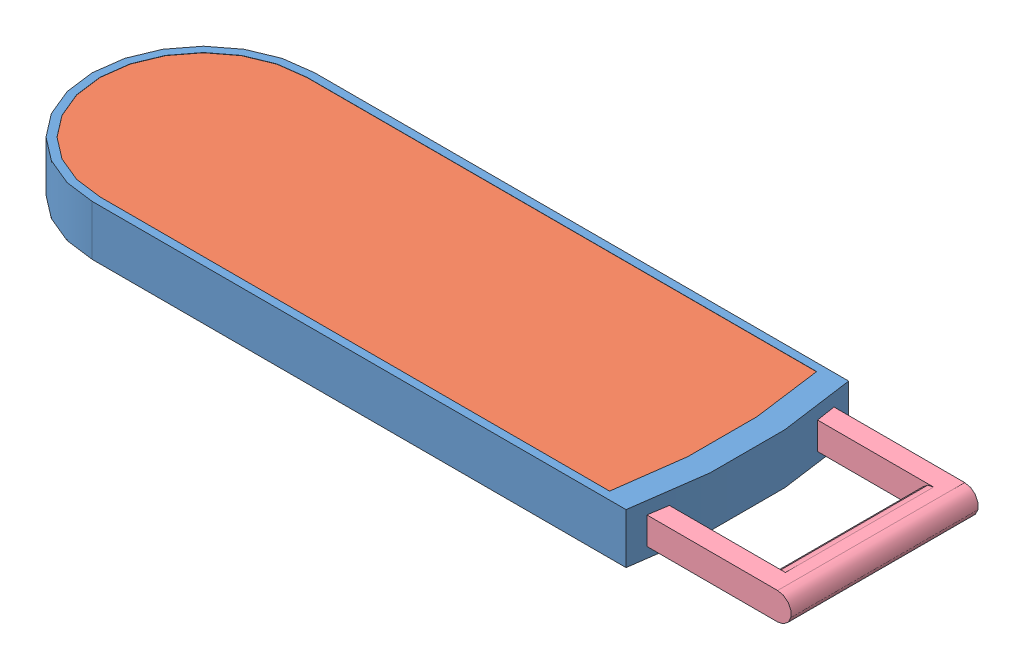
SolidWorks assembly Drawer, configuration Default. Lengths in mm.
Overall size (203.59 12.9 57.15).
4 component instances, 4 part files, 9 mates.
Components (placement in the parent):
- Drawer-1: Drawer [Default] at (12.6564 98.023 116.6708) size (168.57 12.9 57.15)
- Drawer_Cover-1: Drawer_Cover [Default] at (12.6564 106.923 116.6708) size (160.08 1.95 53.15)
- Pb-1: Pb [Default] at (12.6564 98.023 116.6708) size (133.5 8.9 53.15)
- Drawer_Handle-1: Drawer_Handle [Default] at (12.6564 98.923 116.6708) x (1 0 0.000592) z (-0.000592 0 1) size (37.07 7 48)
Mates (geometry in assembly coordinates):
- Coincident4: coincident anti-aligned: plane of Drawer-1 through (12.6564 98.023 116.6708) normal (0 1 0); plane of Pb-1 through (12.6564 98.023 116.6708) normal (0 -1 0)
- Coincident6: coincident anti-aligned: plane of Drawer-1 through (12.6564 108.923 143.2458) normal (0 0 -1); plane of Pb-1 through (12.6564 106.923 143.2458) normal (0 0 1)
- Concentric1: concentric aligned: cylinder of Drawer-1 through (12.6564 108.923 116.6708) axis (0 -1 0) radius 133.5; cylinder of Pb-1 through (12.6564 106.923 116.6708) axis (0 -1 0) radius 133.5
- Coincident7: coincident anti-aligned: plane of Drawer-1 through (12.6564 108.923 143.2458) normal (0 0 -1); plane of Drawer_Cover-1 through (12.6564 108.873 143.2458) normal (0 0 1)
- Coincident8: coincident anti-aligned: plane of Drawer_Cover-1 through (12.6564 106.923 116.6708) normal (0 -1 0); plane of Pb-1 through (12.6564 106.923 116.6708) normal (0 1 0)
- Coincident9: coincident aligned: circle of Drawer-1; cylinder of Drawer_Cover-1 through (12.6564 108.873 116.6708) axis (0 -1 0) radius 133.5
- Concentric2: concentric anti-aligned: cylinder of Drawer-1 through (12.6564 96.023 116.6708) axis (0 1 0) radius 140; cylinder of Drawer_Handle-1 through (12.6564 105.923 116.6708) axis (0 -1 0) radius 140
- Distance2: distance = 4.575 mm: line of Drawer-1 through (149.7092 96.023 145.2458) axis (0 1 0); line of Drawer_Handle-1 through (150.5697 105.923 140.7525) axis (0 -1 0)
- Distance3: distance = 3 mm aligned: plane of Drawer_Handle-1 through (12.6564 105.923 116.6708) normal (0 1 0); plane of Drawer-1 through (12.6564 108.923 116.6708) normal (0 1 0)
